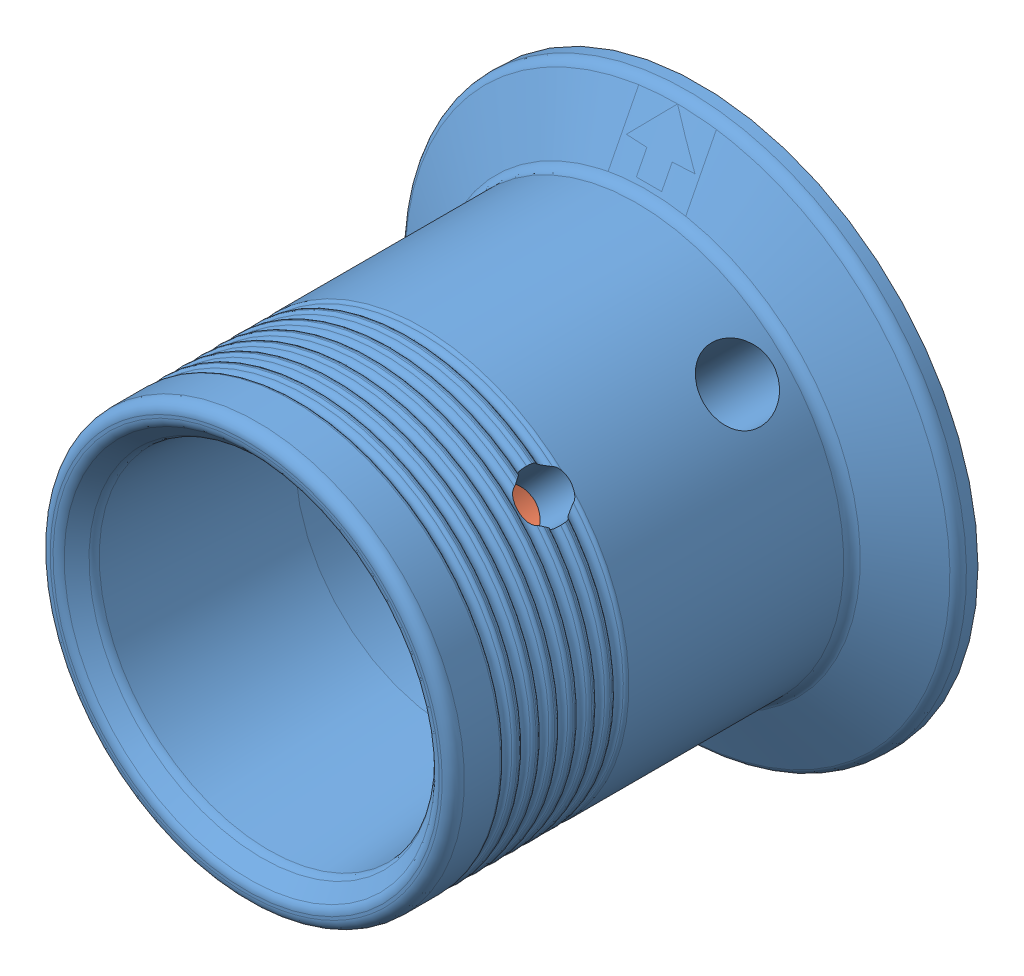
SolidWorks assembly Select JETT Knob, configuration Default. Lengths in mm.
Overall size (38.1 38.1 30.99).
2 component instances, 2 part files, 0 mates.
Components (placement in the parent):
- Select JETT Knob-1: Select JETT Knob [Default] at origin size (38.1 38.1 30.99)
- 9414T600 - COLLAR, SHAFT, .25 ID X .50 OD X .2813 T, STEEL, BLK-1: 9414T600 - COLLAR, SHAFT, .25 ID X .50 OD X .2813 T, STEEL, BLK [9414T6] at (0 0 7.3501) x (0.707107 -0.707107 0) z (0 0 1) size (12.7 12.7 7.14)
